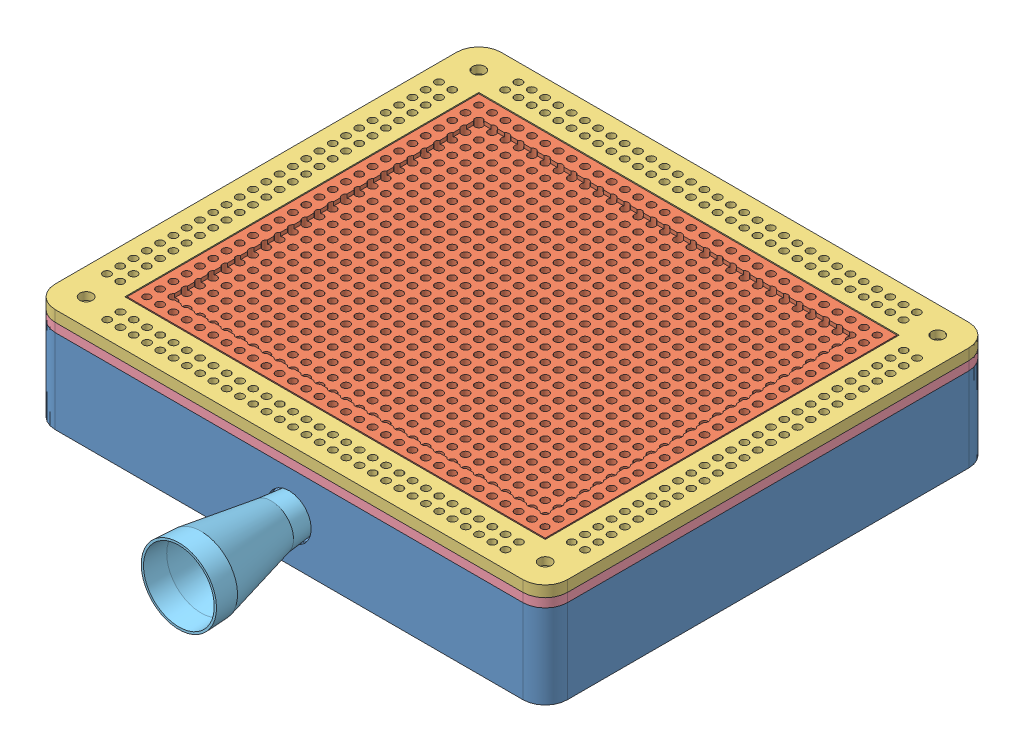
SolidWorks assembly Assembly_TK, configuration Default. Lengths in mm.
Overall size (231.4 49.07 259.4).
5 component instances, 5 part files, 14 mates.
Components (placement in the parent):
- Container_TK-1: Container_TK [Default] at origin size (231.4 38 201.4)
- PCB_holder_TK-1: PCB_holder_TK [Default] at (0 42 0) size (188.9 5 158.9)
- Lifter_TK-1: Lifter_TK [Default] at (0 42 0) size (231.4 7.5 201.4)
- Lid_TK-1: Lid_TK [Default] at (0 38 0) size (231.4 9 201.4)
- nozzel_adapter.step-1: nozzel_adapter.step [Default] at (0 19 78.7) x (-0.819543 -0.573017 0) z (-0.573017 0.819543 0) size (37 60 34)
Mates (geometry in assembly coordinates):
- Coincident1: coincident aligned: plane of Container_TK-1 through (0 0 0) normal (0 0 1)
- Coincident3: coincident aligned: plane of Container_TK-1 through (0 0 0) normal (0 1 0)
- Coincident4: coincident aligned: plane of Container_TK-1 through (0 0 0) normal (1 0 0)
- Coincident5: coincident aligned: plane of Lid_TK-1 through (0 38 0) normal (0 0 1)
- Coincident6: coincident aligned: plane of Lid_TK-1 through (0 38 0) normal (1 0 0)
- Coincident7: coincident anti-aligned: plane of Container_TK-1 through (0 38 0) normal (0 1 0); plane of Lid_TK-1 through (0 38 0) normal (0 -1 0)
- Coincident8: coincident aligned: plane of Lifter_TK-1 through (0 42 0) normal (0 0 1)
- Coincident9: coincident aligned: plane of Lifter_TK-1 through (0 42 0) normal (1 0 0)
- Coincident10: coincident aligned: plane of PCB_holder_TK-1 through (0 42 0) normal (0 0 1)
- Coincident11: coincident aligned: plane of PCB_holder_TK-1 through (0 42 0) normal (1 0 0)
- Coincident12: coincident anti-aligned: plane of Lifter_TK-1 through (0 42 0) normal (0 -1 0); plane of Lid_TK-1 through (0 42 0) normal (0 1 0)
- Coincident13: coincident anti-aligned: plane of PCB_holder_TK-1 through (0 42 0) normal (0 -1 0); plane of Lid_TK-1 through (0 42 0) normal (0 1 0)
- Coincident14: coincident anti-aligned: circle of Container_TK-1; plane of nozzel_adapter.step-1 through (0 19 98.7) normal (0 0 -1)
- Concentric1: concentric aligned: cylinder of Container_TK-1 through (0 19 98.7) axis (0 0 1) radius 10; circle of nozzel_adapter.step-1
